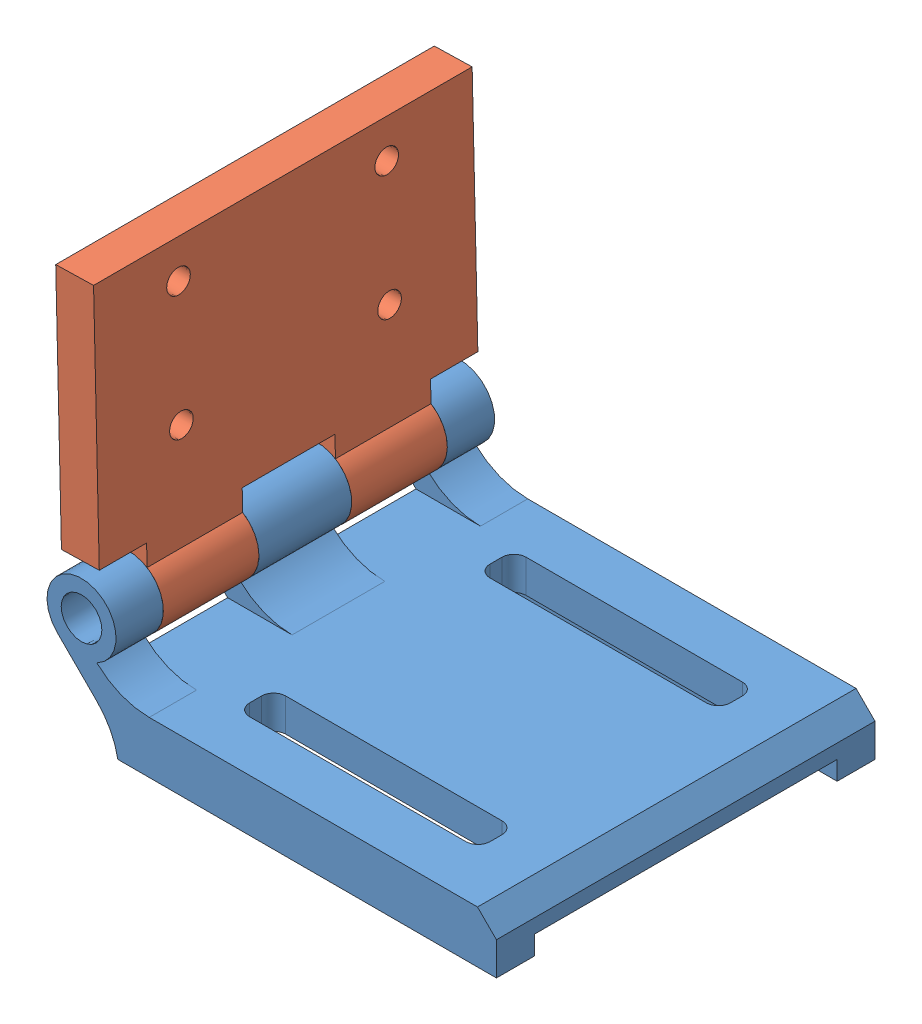
SolidWorks assembly 摄像头架, configuration 默认. Lengths in mm.
Overall size (47.88 42.12 40).
2 component instances, 2 part files, 2 mates.
Components (placement in the parent):
- 底-1: 底 [默认] at origin size (47.49 14.65 40)
- 架-1: 架 [默认] at (-23.8381 7.25 0) x (0 0 1) z (0.99992 0.012641 0) size (40 34.72 7.3)
Mates (geometry in assembly coordinates):
- 同心2: concentric aligned: circle of 底-1; circle of 架-1
- 重合3: coincident anti-aligned: plane of 底-1 through (20 11.75 5) normal (0 0 1); plane of 架-1 through (-32.9591 12.3165 5) normal (0 0 -1)
